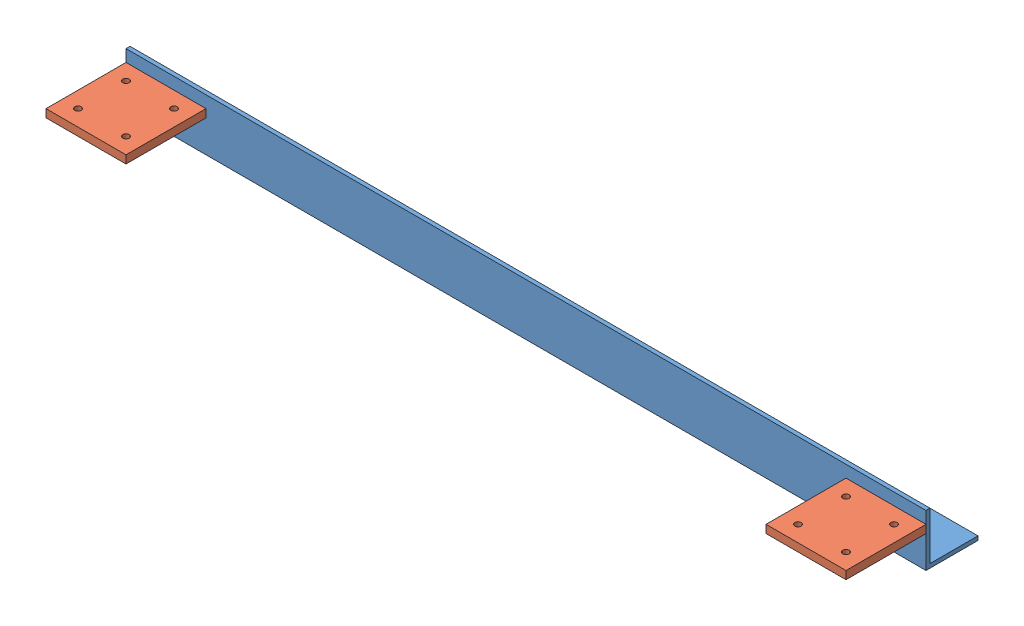
SolidWorks assembly БОК, configuration По умолчанию. Lengths in mm.
Overall size (1000 65 165).
3 component instances, 2 part files, 7 mates.
Components (placement in the parent):
- СТбок-1: СТбок [По умолчанию] at origin size (1000 65 65)
- ПланкаУГл-1: ПланкаУГл [По умолчанию] at (50 40 50) size (100 10 100)
- ПланкаУГл-2: ПланкаУГл [По умолчанию] at (950 40 50) size (100 10 100)
Mates (geometry in assembly coordinates):
- Совпадение1: coordinate: point of СТбок-1; point of assembly
- Совпадение2: coincident anti-aligned: plane of СТбок-1 through (1000 0 0) normal (0 0 1); plane of ПланкаУГл-2 through (900 50 0) normal (0 0 -1)
- Расстояние1: distance = 40 mm aligned: plane of ПланкаУГл-2 through (950 40 50) normal (0 -1 0); plane of СТбок-1 through (1000 0 0) normal (0 -1 0)
- Совпадение9: coincident aligned: plane of СТбок-1 through (1000 0 0) normal (1 0 0); plane of ПланкаУГл-2 through (1000 50 100) normal (1 0 0)
- Совпадение10: coincident aligned: plane of ПланкаУГл-1 through (50 40 50) normal (0 -1 0); plane of ПланкаУГл-2 through (950 40 50) normal (0 -1 0)
- Совпадение8: coincident aligned: plane of СТбок-1 through (0 0 0) normal (-1 0 0); plane of ПланкаУГл-1 through (0 20 100) normal (-1 0 0)
- Совпадение7: coincident anti-aligned: plane of СТбок-1 through (1000 0 0) normal (0 0 1); plane of ПланкаУГл-1 through (0 20 0) normal (0 0 -1)
